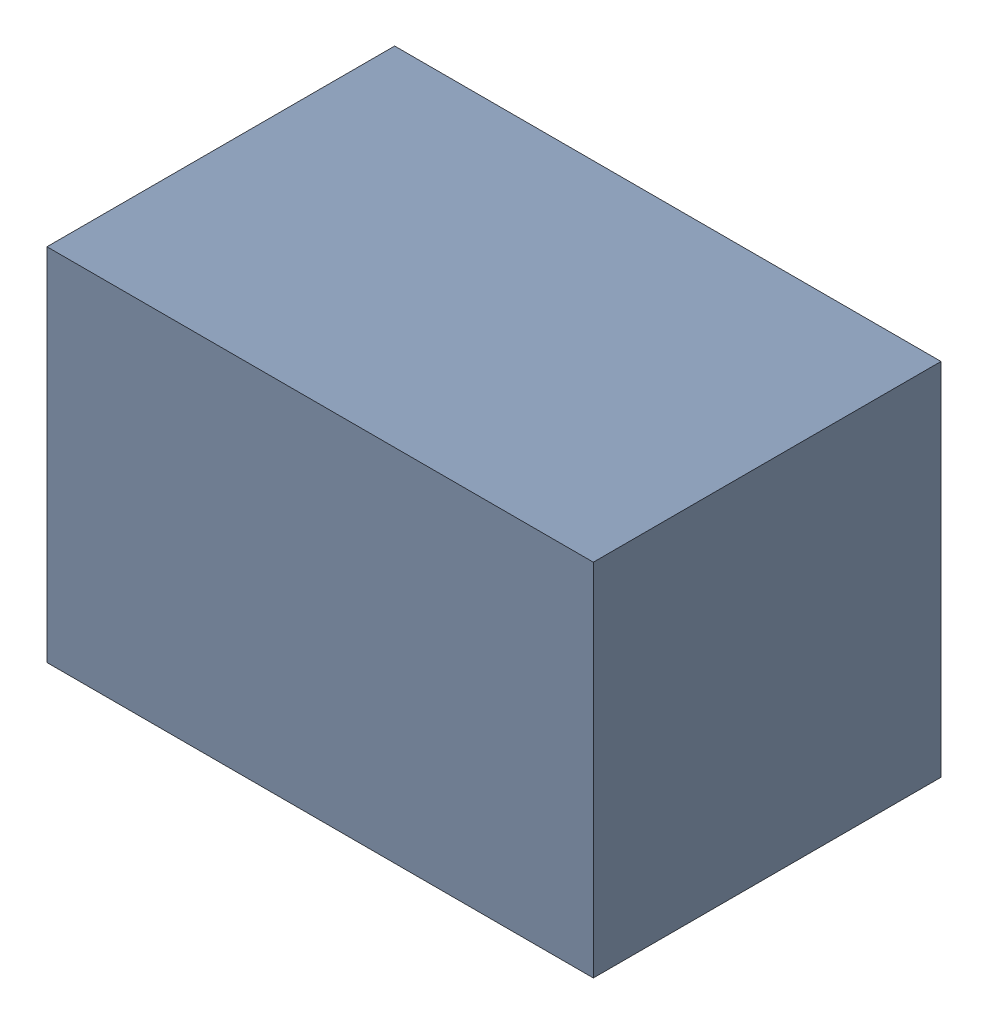
SolidWorks assembly C23, configuration Default. Lengths in mm.
Overall size (2.2 1.45 1.4).
2 component instances, 1 part files, 0 mates.
Components (placement in the parent):
- 1017092848-1: 1017092848 [Default] at (137.16 144.78 0) size (2.2 1.45 1.4)
  - Extruded_3-1: Extruded_3 [Default] at origin size (2.2 1.45 1.4)
